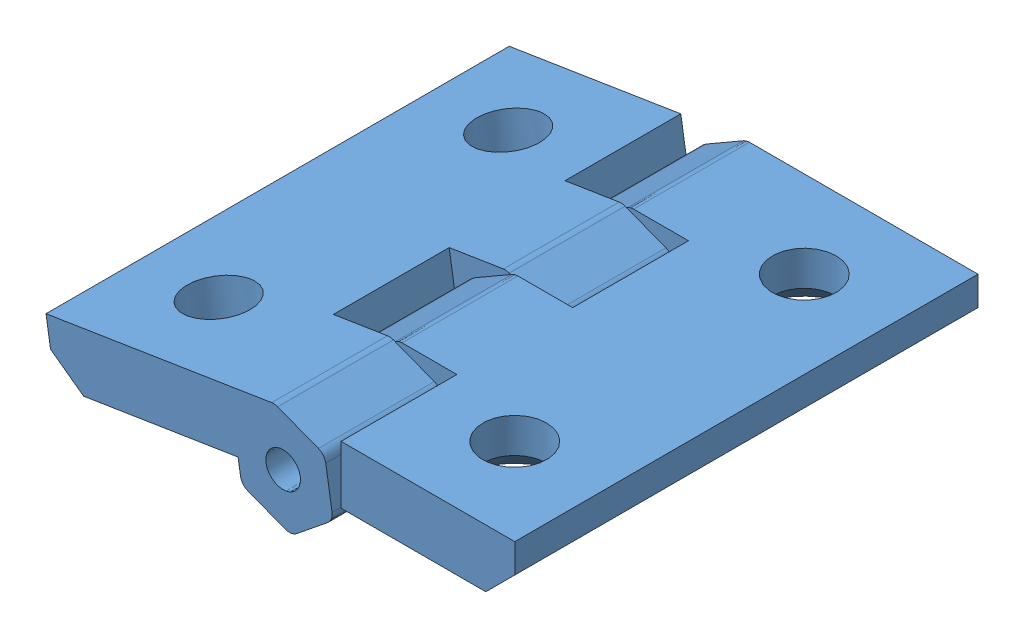
SolidWorks assembly 铰链, configuration 默认. Lengths in mm.
Overall size (40.48 12.73 40).
2 component instances, 1 part files, 2 mates.
Components (placement in the parent):
- 铰链-1: 铰链 [默认] at (-11.391 1.5222 20) size (24 9.08 40)
- 铰链-2: 铰链 [默认] at (-11.391 1.5222 60) x (-0.987641 -0.156733 0) z (0 0 -1) size (24 9.08 40)
Mates (geometry in assembly coordinates):
- Concentric1: concentric: cylinder of assembly; cylinder of assembly; cylinder of 铰链-1 through (-11.391 1.5222 60) axis (0 0 -1) radius 1.5; cylinder of 铰链-2 through (-11.391 1.5222 20) axis (0 0 1) radius 1.5
- Coincident1: coincident: plane of assembly; plane of assembly; plane of 铰链-1 through (-11.391 1.5222 60) normal (0 0 1); plane of 铰链-2 through (-11.391 1.5222 60) normal (0 0 1)
